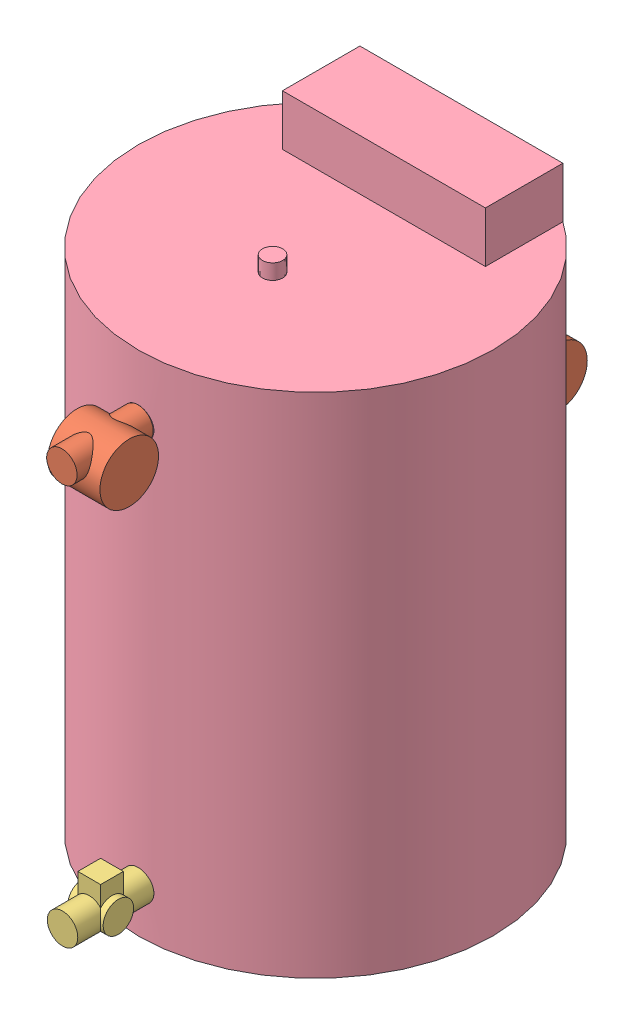
SolidWorks assembly Assem1, configuration Default. Lengths in mm.
Overall size (700 1100 980.26).
6 component instances, 4 part files, 16 mates.
Components (placement in the parent):
- bend-1: bend [Default] at (-500.0831 473.2236 -96.3426) size (60 90 80)
- meter-1: meter [Default] at (-500.0831 113.2236 -146.3426) size (103 150 115.54)
- sol-1: sol [Default] at (-500.0831 263.2236 -146.3426) x (-1 0 0) z (0 0 -1) size (70 150 90)
- tank-1: tank [Default] at (-500.0831 -403.1612 253.6574) size (700 1100 700)
- meter-2: meter [Default] at (-500.0831 473.2236 753.6574) x (1 0 0) z (0 1 0) size (103 150 115.54)
- sol-2: sol [Default] at (-500.0831 -316.2659 752.3693) x (1 0 0) z (0 1 0) size (70 150 90)
Mates (geometry in assembly coordinates):
- Concentric2: concentric anti-aligned: cylinder of bend-1 through (-500.0831 473.2236 -96.3426) axis (0 0 -1) radius 30; cylinder of tank-1 through (-500.0831 473.2236 -96.3426) axis (0 0 1) radius 30
- Parallel1: parallel anti-aligned: plane of bend-1 through (-500.0831 413.2236 -146.3426) normal (0 -1 0)
- Coincident2: coincident anti-aligned: plane of bend-1 through (-500.0831 413.2236 -146.3426) normal (0 -1 0); plane of sol-1 through (-500.0831 413.2236 -146.3426) normal (0 1 0)
- Coincident3: coincident aligned: circle of bend-1; circle of sol-1
- Coincident4: coincident aligned: circle of meter-1; circle of sol-1
- Parallel2: parallel anti-aligned: plane of meter-1 through (-548.0831 190.9551 -168.8369) normal (-1 0 0)
- Concentric4: concentric aligned: cylinder of bend-1 through (-500.0831 539.3236 -146.3426) axis (0 -1 0) radius 30; cylinder of sol-1 through (-500.0831 413.2236 -146.3426) axis (0 -1 0) radius 30
- Lock1: lock: unknown of meter-1; unknown of sol-1
- Lock2: lock: unknown of bend-1; unknown of sol-1
- Tangent5: tangent: curve of bend-1; curve of tank-1
- Concentric8: concentric aligned: cylinder of tank-1 through (-500.0831 473.2236 -96.3426) axis (0 0 1) radius 30; cylinder of meter-2 through (-500.0831 473.2236 603.6574) axis (0 0 1) radius 30
- Tangent7: tangent: curve of tank-1; circle of meter-2
- Parallel5: parallel aligned: plane of meter-2 through (-445.0831 450.7293 675.9258) normal (1 0 0)
- Concentric9: concentric anti-aligned: cylinder of tank-1 through (-500.0831 -316.2659 603.6574) axis (0 0 -1) radius 30; cylinder of sol-2 through (-500.0831 -316.2659 602.3693) axis (0 0 1) radius 30
- Tangent8: tangent: curve of tank-1; circle of sol-2
- Parallel8: parallel aligned: plane of sol-2 through (-500.0831 -256.2659 752.3693) normal (0 1 0)
